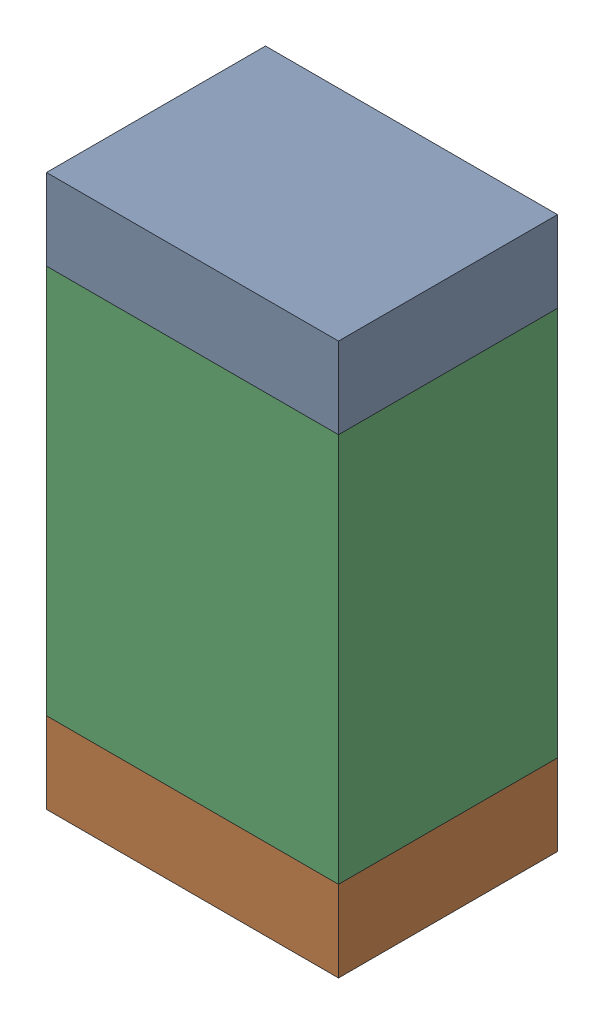
SolidWorks assembly C1, configuration 默认. Lengths in mm.
Overall size (1.8 3.4 1.35).
6 component instances, 2 part files, 0 mates.
Components (placement in the parent):
- 6241790576-1: 6241790576 [默认] at (18.923 26.977 -3.0414) size (1.8 0.5 1.35)
  - Extruded-2-1: Extruded-2 [默认] at origin size (1.8 0.5 1.35)
- 6241790576-2: 6241790576 [默认] at (18.923 24.077 -3.0414) size (1.8 0.5 1.35)
  - Extruded-2-1: Extruded-2 [默认] at origin size (1.8 0.5 1.35)
- 6241790896-1: 6241790896 [默认] at (18.923 25.527 -3.0414) size (1.8 2.4 1.35)
  - Extruded-3-1: Extruded-3 [默认] at origin size (1.8 2.4 1.35)
